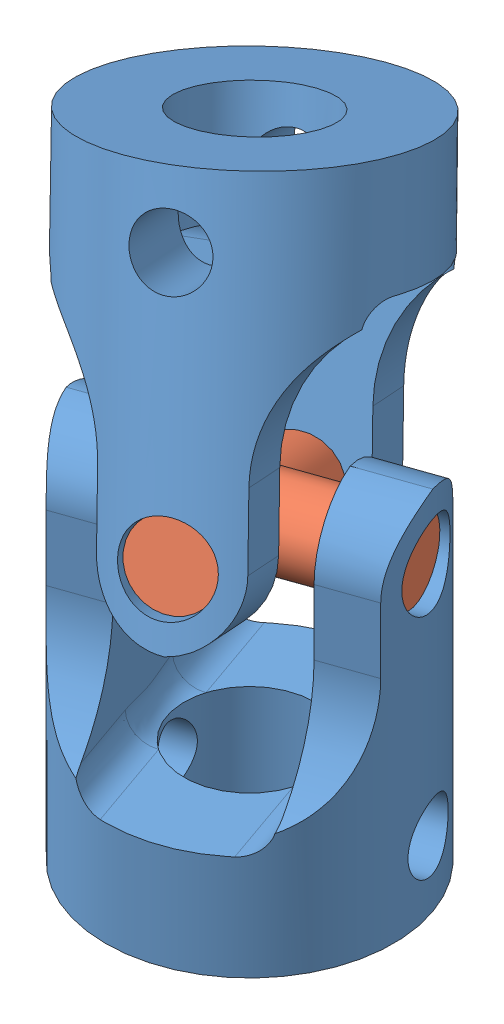
SolidWorks assembly U-joint, configuration Default. Lengths in mm.
Overall size (16.51 24.62 17).
3 component instances, 2 part files, 8 mates.
Components (placement in the parent):
- u-joint-1: u-joint [Default] x (0.330447 0 0.943825) z (-0.943825 0 0.330447) size (11 14 11)
- u-joint middle-1: u-joint middle [Default] at (0 11.5 0) x (-0.317657 -0.275522 -0.907294) z (-0.943825 0 0.330447) size (10 2.95 10)
- u-joint-2: u-joint [Default] at (-2.3229 22.4774 -2.5203) x (0.926441 0.113652 -0.358874) z (-0.317657 -0.275522 -0.907294) size (11 14 11)
Mates (geometry in assembly coordinates):
- Concentric1: concentric anti-aligned: cylinder of u-joint-1 through (5.191 11.5 -1.8175) axis (-0.943825 0 0.330447) radius 1.5; cylinder of u-joint middle-1 through (-4.7191 11.5 1.6522) axis (0.943825 0 -0.330447) radius 1.475
- Distance1: distance = 5 mm: cylinder of u-joint-1 through (0 4 0) axis (0 -1 0) radius 5.5; plane of u-joint middle-1 through (-4.7191 11.5 1.6522) normal (-0.943825 0 0.330447)
- Concentric2: concentric anti-aligned: cylinder of u-joint middle-1 through (-1.5883 10.1224 -4.5365) axis (0.317657 0.275522 0.907294) radius 1.475; cylinder of u-joint-2 through (1.7471 13.0154 4.9901) axis (-0.317657 -0.275522 -0.907294) radius 1.5
- Distance2: distance = 5 mm: plane of u-joint middle-1 through (-1.5883 10.1224 -4.5365) normal (-0.317657 -0.275522 -0.907294); cylinder of u-joint-2 through (-1.515 18.6591 -1.6436) axis (-0.201993 0.954553 -0.219152) radius 5.5
- Concentric3: concentric: cylinder of u-joint-1 through (0 4 0) axis (0 -1 0) radius 2.5
- Coincident2: coincident anti-aligned: plane of u-joint-1 through (0 0 0) normal (0 -1 0)
- LimitAngle1: limit planar angle = 0.118505 rad anti-aligned: plane of u-joint-1 through (0 0 0) normal (-0.943825 0 0.330447); plane of u-joint-2 through (-2.3229 22.4774 -2.5203) normal (0.926441 0.113652 -0.358874)
- LimitAngle2: limit planar angle = 0.279133 rad anti-aligned: plane of u-joint-1 through (0 0 0) normal (0.330447 0 0.943825); plane of u-joint-2 through (-2.3229 22.4774 -2.5203) normal (-0.317657 -0.275522 -0.907294)
